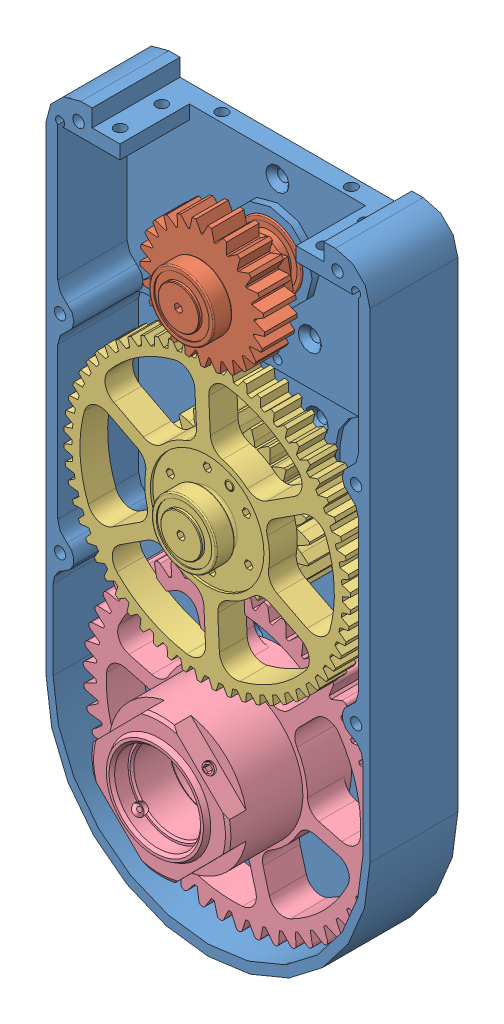
SolidWorks assembly CompundGears-1, configuration Default. Lengths in mm.
Overall size (183.67 314.43 79).
4 component instances, 4 part files, 8 mates.
Components (placement in the parent):
- gbox_housing-1-1: gbox_housing-1 [Default] at origin size (140 292.6 38)
- gbox_input-1-1: gbox_input-1 [Default] at (0 0 50.8) x (0.194268 -0.980948 0) z (0 0 1) size (54 53.89 68.8)
- gbox_middle-1-1: gbox_middle-1 [Default] at (0 -85.75 49.7) x (-0.456802 -0.889568 0) z (0 0 1) size (124 124 51.5)
- gbox_output-1-1: gbox_output-1 [Default] at (0 -179.1 10) x (-0.711201 0.702989 0) z (0 0 -1) size (130 129.75 53)
Mates (geometry in assembly coordinates):
- Coincident1: coincident aligned: plane of gbox_housing-1-1 through (18 0 11) normal (0 0 1); plane of gbox_input-1-1 through (0 0 11) normal (0 0 1)
- Concentric1: concentric anti-aligned: cylinder of gbox_housing-1-1 through (0 0 11) axis (0 0 -1) radius 14; cylinder of gbox_input-1-1 through (0 0 3.1) axis (0 0 1) radius 14
- Distance1: distance = 2 mm anti-aligned: plane of gbox_output-1-1 through (0 -179.1 8) normal (0 0 -1); plane of gbox_housing-1-1 through (19 -179.1 6) normal (0 0 1)
- Concentric2: concentric anti-aligned: cylinder of gbox_housing-1-1 through (0 -179.1 30) axis (0 0 -1) radius 12.48; cylinder of gbox_output-1-1 through (0 -179.1 9.25) axis (0 0 1) radius 12.5
- Coincident3: coincident aligned: plane of gbox_housing-1-1 through (0 -179.1 0) normal (0 0 -1); plane of gbox_middle-1-1 through (0 -85.75 0) normal (0 0 -1)
- Concentric3: concentric anti-aligned: cylinder of gbox_middle-1-1 through (0 -85.75 7.9) axis (0 0 -1) radius 14; cylinder of gbox_housing-1-1 through (0 -85.75 0) axis (0 0 1) radius 14
- GearMate1: gear = 120 : 50 mm: line of gbox_input-1-1 through (0 0 -0.285) axis (0 0 1); line of gbox_middle-1-1 through (0 -85.75 -4.375) axis (0 0 1)
- GearMate2: gear = 125 : 60 mm: line of gbox_middle-1-1 through (0 -85.75 -4.375) axis (0 0 1); line of gbox_output-1-1 through (0 -179.1 5.35) axis (0 0 1)
